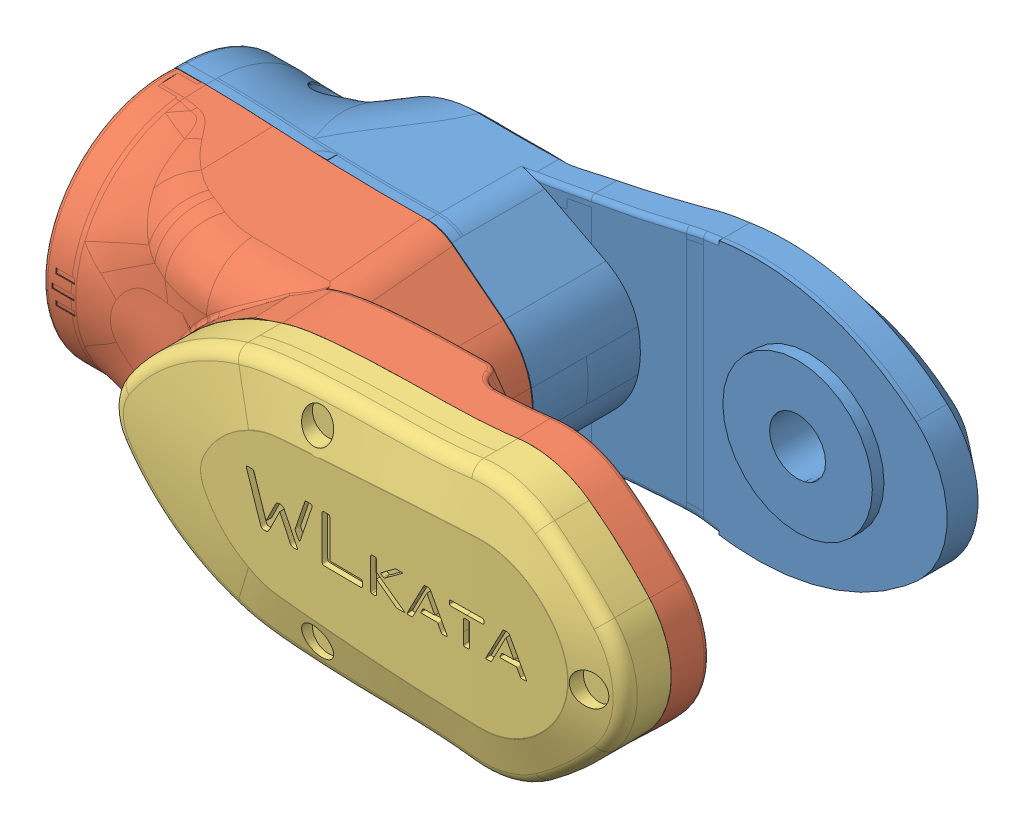
SolidWorks assembly Mirobot_Link4, configuration 默认. Lengths in mm.
Overall size (73.76 38.7 46.95).
3 component instances, 3 part files, 3 mates.
Components (placement in the parent):
- 13小臂左-1: 13小臂左 [默认] at (-50.6649 3.4687 82.8928) x (0 1 0) z (0 0 -1) size (37.72 71.11 23.56)
- 13小臂右-1: 13小臂右 [默认] at (-50.3902 3.4629 82.8928) x (0 1 0) z (0 0 1) size (32.12 73.76 17.35)
- 14小臂右盖-2: 14小臂右盖 [默认] at (49.5493 33.4629 99.9428) x (0 1 0) z (0 0 1) size (32.23 55.01 6.34)
Mates (geometry in assembly coordinates):
- 重合3: coincident anti-aligned: plane of 13小臂右-1 through (2.238 -9.7088 99.9428) normal (0 0 1); plane of 14小臂右盖-2 through (20.1778 3.463 99.9428) normal (0 0 -1)
- 同心1: concentric aligned: cone of 13小臂右-1 through (-15.2559 3.463 98.366) axis (0 0 1); cylinder of 14小臂右盖-2 through (-15.2559 3.463 40.5388) axis (0 0 1) radius 5.0113
- 重合6: coincident anti-aligned: plane of 13小臂左-1 through (-50.6649 3.4687 82.8928) normal (0 0 1); plane of 13小臂右-1 through (20.1778 3.463 82.8928) normal (0 0 -1)
